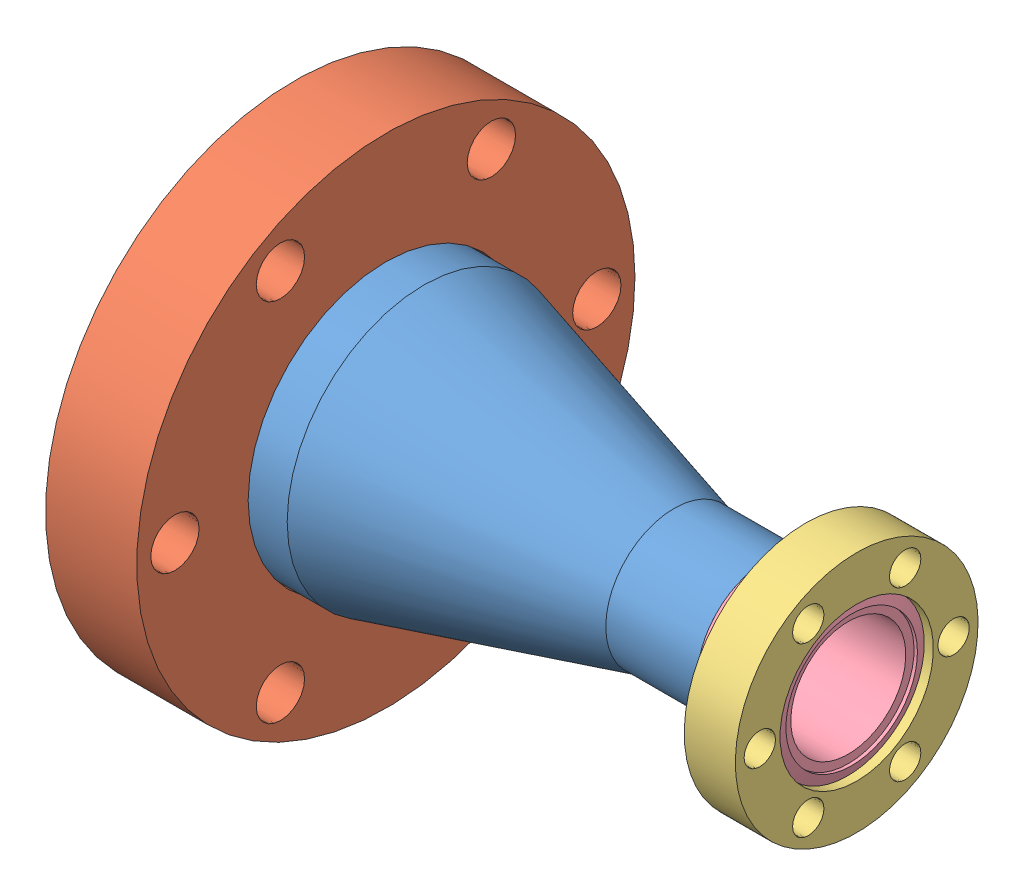
SolidWorks assembly Conical Adapter 1.33-2.752, configuration Default. Lengths in mm.
Overall size (78.23 69.34 69.34).
5 component instances, 4 part files, 0 mates.
Components (placement in the parent):
- 402030-001-1: 402030-001 [Default] at origin size (60.22 38.1 38.1)
- 110014 (2.75 X 1.5 NR)-1: 110014 (2.75 X 1.5 NR) [Default] at (1.0414 0 0) x (-1 0 0) z (0 0 -1) size (12.7 69.34 69.34)
- 100004 (1.33 X .75 R)-1: 100004 (1.33 X .75 R) [Default] at (72.9234 0 0) x (-1 0 0) z (0 0 -1) size (14.22 33.78 33.78)
  - 100004 (1.33 X .75 REC)-1: 100004 (1.33 X .75 REC) [Default] at origin size (7.11 33.78 33.78)
  - 100004 (1.33 X .75 INS)-1: 100004 (1.33 X .75 INS) [Default] at (1.17 0 0) x (1 0 0) z (0 0.470241 -0.882538) size (13.52 21.3 21.3)
